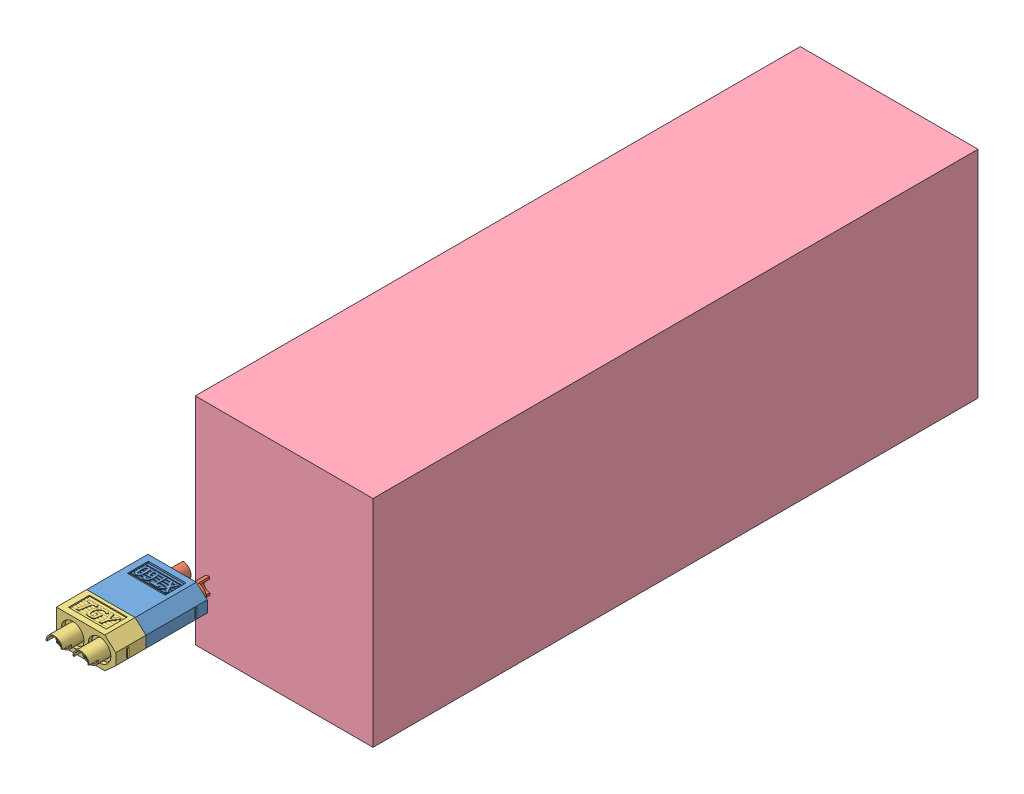
SolidWorks assembly Сборка2, configuration По умолчанию. Lengths in mm.
Overall size (55.42 66.42 241.04).
6 component instances, 4 part files, 1 mates.
Components (placement in the parent):
- XT-60_Macho-1: XT-60_Macho [Valor predeterminado] at (53.9131 -8.7888 32.5686) size (16.3 8.2 41.1)
  - XT-60_Macho-1: XT-60_Macho [Valor predeterminado] at (-37.9952 28.536 -8.1) size (16.3 8.2 16.2)
  - PinoXT-60_Macho-1: PinoXT-60_Macho [Valor predeterminado] at (-26.6452 32.636 -13.1) x (-0.008124 0.999967 0) z (0.999967 0.008124 0) size (4.3 26.83 4.3)
  - PinoXT-60_Macho-2: PinoXT-60_Macho [Valor predeterminado] at (-33.7452 32.636 -13.1) x (-0.014321 -0.999897 0) z (-0.999897 0.014321 0) size (4.3 26.83 4.3)
  - XT-60_Macho 1-1: XT-60_Macho 1 [Valor predeterminado] at (-37.9952 36.736 16.1) x (1 0 0) z (0 0 -1) size (16.3 8.2 21.5)
- Black Magic Li-Po 22.2V-1: Black Magic Li-Po 22.2V [По умолчанию] at (-23.5 -9.9724 -107.4731) x (0 0 -1) z (1 0 0) size (160 57 47)
Mates (geometry in assembly coordinates):
- Симметричный1: symmetric aligned: plane of Black Magic Li-Po 22.2V-1 through (23.5 -9.9724 -107.4731) normal (1 0 0); plane of Black Magic Li-Po 22.2V-1 through (-23.5 -9.9724 -107.4731) normal (-1 0 0); plane of assembly through (0 0 0) normal (1 0 0)
